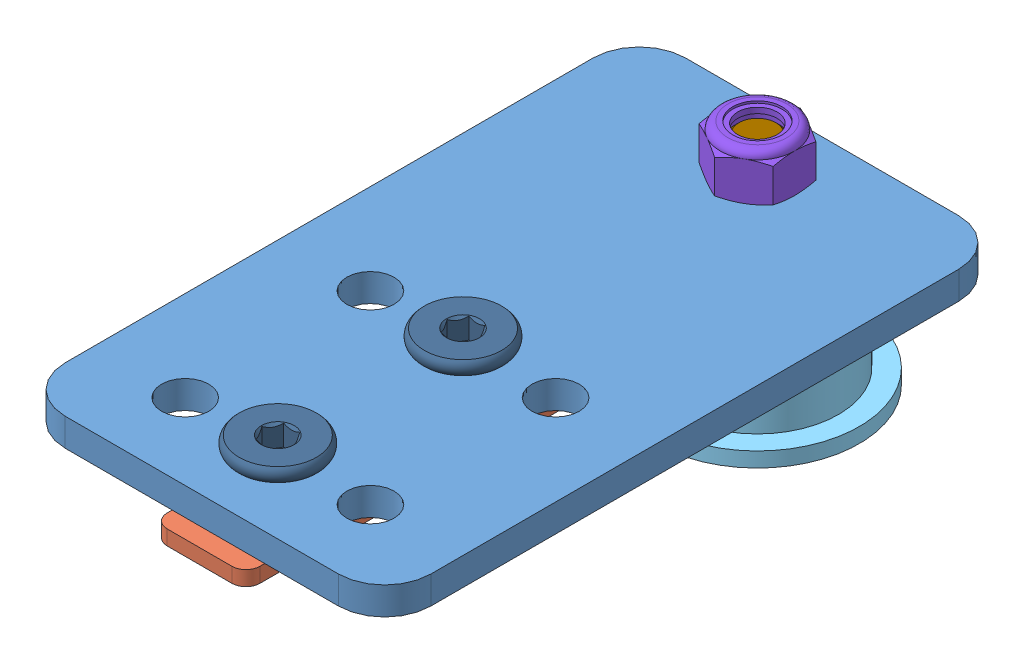
SolidWorks assembly FREE_IDLER_PULLEY, configuration Default. Lengths in mm.
Overall size (39.5 27.8 74.01).
13 component instances, 10 part files, 18 mates.
Components (placement in the parent):
- Idler Pulley Plate-1: Idler Pulley Plate [Default] at (16.1031 32.5465 56.7514) size (39.5 3 67)
- Double Tee Nut-1: Double Tee Nut [Default] at (11.1031 30.7465 90.4814) x (0 0 -1) z (0 -1 0) size (36.88 10 3)
- Slot Washer 15 x 5 x 2-1: Slot Washer 15 x 5 x 2 [Default] at (16.1031 32.5465 30.2514) x (0.848345 0 0.529443) z (0.529443 0 -0.848345) size (15 2 15)
- Ball Bearing 5 x 16 x 5-1: Ball Bearing 5 x 16 x 5 [Default] at (16.1031 26.0465 30.2514) x (0 1 0) z (0.24833 0 0.968675) size (5 16 16)
- Smooth Idler Pulley Wheel-1: Smooth Idler Pulley Wheel [Default] at (16.1031 22.1965 30.2514) x (0 1 0) z (-0.954606 0 0.297871) size (12.7 22 22)
- Nylon Spacer 0.125in-1: Nylon Spacer 0.125in [Default] at (16.1031 20.3715 30.2514) size (7.94 3.17 7.94)
- Ball Bearing 5 x 16 x 5-2: Ball Bearing 5 x 16 x 5 [Default] at (16.1031 17.8715 30.2514) x (0 1 0) z (-0.015901 0 0.999874) size (5 16 16)
- Slot Washer 15 x 5 x 2-2: Slot Washer 15 x 5 x 2 [Default] at (16.1031 30.5465 30.2514) x (0.837169 0 0.546944) z (0.546944 0 -0.837169) size (15 2 15)
- Precision Shim 8 x 5 x 1-1: Precision Shim 8 x 5 x 1 [Default] at (16.1031 15.3715 30.2514) x (0.837169 0 0.546944) z (0.546944 0 -0.837169) size (8 1 8)
- Nylon Insert Lock Nut M5-1: Nylon Insert Lock Nut M5 [Default] at (16.1031 35.5465 30.2514) size (8 5 9.24)
- Low Profile Screw M5-2: Low Profile Screw M5 [M5 x 25] at (16.1031 39.3715 30.2514) x (0 1 0) z (0 0 1) size (26.62 9 9)
- LP_SH_SCREW_M5_8mm-2: LP_SH_SCREW_M5_8mm [M5 x 8] at (16.1031 27.5465 62.0414) x (0 -1 0) z (0 0 1) size (9.62 9 9)
- LP_SH_SCREW_M5_8mm-3: LP_SH_SCREW_M5_8mm [M5 x 8] at (16.1031 27.5465 82.0414) x (0 -1 0) z (0 0 1) size (9.62 9 9)
Mates (geometry in assembly coordinates):
- Concentric1: concentric aligned: cylinder of Idler Pulley Plate-1 through (16.1031 35.5465 62.0414) axis (0 -1 0) radius 2.55; cylinder of Double Tee Nut-1 through (16.1031 27.7465 62.0414) axis (0 -1 0) radius 2.1
- Concentric2: concentric aligned: cylinder of Idler Pulley Plate-1 through (16.1031 35.5465 82.0414) axis (0 -1 0) radius 2.55; cylinder of Double Tee Nut-1 through (16.1031 27.7465 82.0414) axis (0 -1 0) radius 2.1
- Distance1: distance = 1.8 mm anti-aligned: plane of Double Tee Nut-1 through (19.6031 30.7465 55.1014) normal (0 1 0); plane of Idler Pulley Plate-1 through (1.3531 32.5465 85.2514) normal (0 -1 0)
- Coincident3: coincident anti-aligned: plane of Ball Bearing 5 x 16 x 5-1 through (13.6814 23.5465 30.8723) normal (0 -1 0); plane of Nylon Spacer 0.125in-1 through (16.1031 23.5465 30.2514) normal (0 1 0)
- Coincident4: coincident anti-aligned: plane of Nylon Spacer 0.125in-1 through (16.1031 20.3715 30.2514) normal (0 -1 0); plane of Ball Bearing 5 x 16 x 5-2 through (13.6034 20.3715 30.2117) normal (0 1 0)
- Coincident5: coincident aligned: plane of Ball Bearing 5 x 16 x 5-1 through (9.5161 28.5465 31.9401) normal (0 1 0); plane of Smooth Idler Pulley Wheel-1 through (13.7201 28.5465 22.6146) normal (0 1 0)
- Coincident6: coincident anti-aligned: plane of Idler Pulley Plate-1 through (1.3531 32.5465 85.2514) normal (0 -1 0); plane of Slot Washer 15 x 5 x 2-1 through (16.1031 32.5465 30.2514) normal (0 1 0)
- Coincident8: coincident anti-aligned: plane of Slot Washer 15 x 5 x 2-1 through (16.1031 30.5465 30.2514) normal (0 -1 0); plane of Slot Washer 15 x 5 x 2-2 through (16.1031 30.5465 30.2514) normal (0 1 0)
- Coincident9: coincident anti-aligned: plane of Ball Bearing 5 x 16 x 5-1 through (9.5161 28.5465 31.9401) normal (0 1 0); plane of Slot Washer 15 x 5 x 2-2 through (16.1031 28.5465 30.2514) normal (0 -1 0)
- Coincident12: coincident anti-aligned: plane of Ball Bearing 5 x 16 x 5-2 through (13.6034 15.3715 30.2117) normal (0 -1 0); plane of Precision Shim 8 x 5 x 1-1 through (16.1031 15.3715 30.2514) normal (0 1 0)
- Concentric13: concentric anti-aligned: cylinder of Idler Pulley Plate-1 through (16.1031 35.5465 30.2514) axis (0 -1 0) radius 2.55; cylinder of Low Profile Screw M5-2 through (16.1031 14.3715 30.2514) axis (0 1 0) radius 2.5
- Concentric14: concentric anti-aligned: cylinder of Nylon Insert Lock Nut M5-1 through (16.1031 35.5465 30.2514) axis (0 -1 0) radius 2.5; cylinder of Low Profile Screw M5-2 through (16.1031 14.3715 30.2514) axis (0 1 0) radius 2.5
- Coincident14: coincident anti-aligned: plane of Idler Pulley Plate-1 through (1.3531 35.5465 85.2514) normal (0 1 0); plane of Nylon Insert Lock Nut M5-1 through (13.6031 35.5465 30.2514) normal (0 -1 0)
- Coincident15: coincident anti-aligned: plane of Precision Shim 8 x 5 x 1-1 through (16.1031 14.3715 30.2514) normal (0 -1 0); plane of Low Profile Screw M5-2 through (11.9416 14.3715 30.2514) normal (0 1 0)
- Concentric161: concentric aligned: cylinder of Idler Pulley Plate-1 through (16.1031 35.5465 62.0414) axis (0 -1 0) radius 2.55; cylinder of LP_SH_SCREW_M5_8mm-2 through (16.1031 35.5465 62.0414) axis (0 -1 0) radius 2.5
- Coincident171: coincident anti-aligned: plane of Idler Pulley Plate-1 through (1.3531 35.5465 85.2514) normal (0 1 0); plane of LP_SH_SCREW_M5_8mm-2 through (20.2645 35.5465 62.0414) normal (0 -1 0)
- Concentric17: concentric aligned: cylinder of Idler Pulley Plate-1 through (16.1031 35.5465 82.0414) axis (0 -1 0) radius 2.55; cylinder of LP_SH_SCREW_M5_8mm-3 through (16.1031 35.5465 82.0414) axis (0 -1 0) radius 2.5
- Coincident19: coincident anti-aligned: plane of Idler Pulley Plate-1 through (1.3531 35.5465 85.2514) normal (0 1 0); plane of LP_SH_SCREW_M5_8mm-3 through (20.2645 35.5465 82.0414) normal (0 -1 0)
